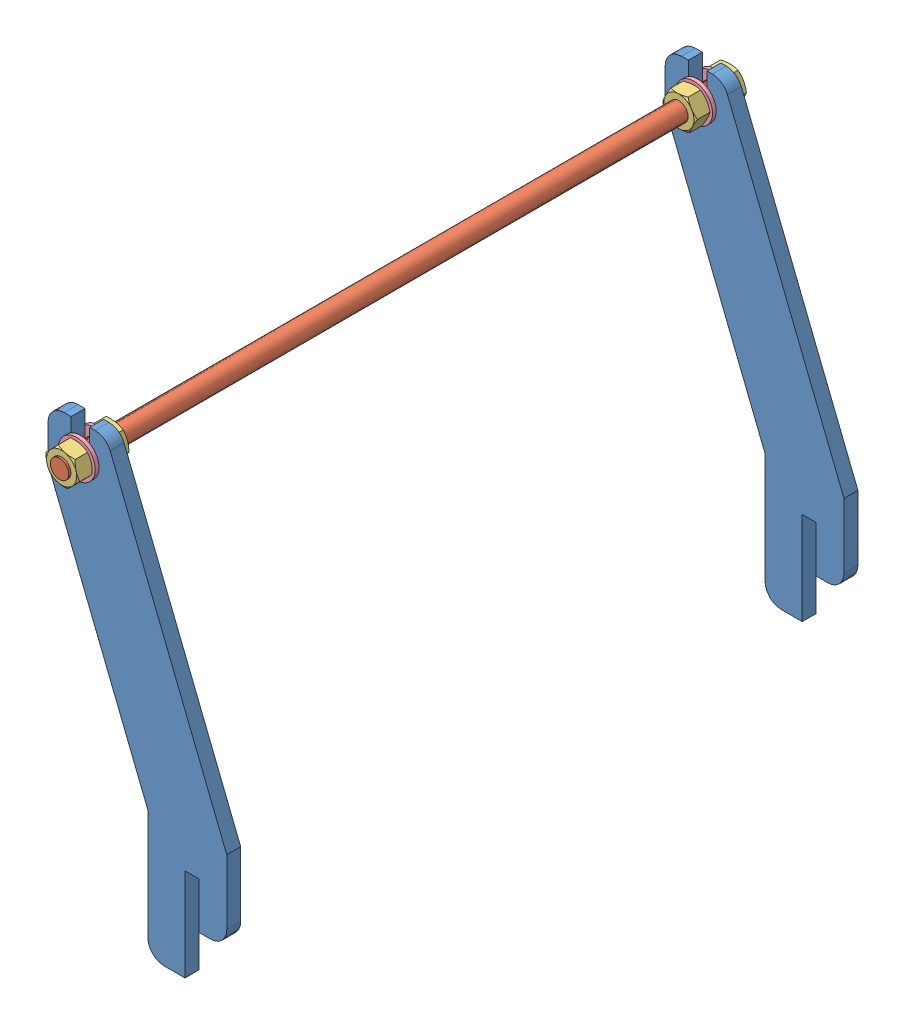
SolidWorks assembly Assembly spool-holder, configuration Valor predeterminado. Lengths in mm.
Overall size (77.07 185 290).
11 component instances, 4 part files, 22 mates.
Components (placement in the parent):
- spool-holder-1: spool-holder [Valor predeterminado] at (-111.4364 -194.1927 182) size (77.07 185 6)
- spool-holder-2: spool-holder [Valor predeterminado] at (-111.4364 -194.1927 448) size (77.07 185 6)
- Threaded Rod DIN 975 - M8 x 290-1: Threaded Rod DIN 975 - M8 x 290 [Valor predeterminado] at (42.0823 58.8982 318) size (8 8 290)
- Nut DIN 934 - M8-1: Nut DIN 934 - M8 [Valor predeterminado] at (42.0823 58.8982 177.15) x (0 0 -1) z (0.514233 0.857651 0) size (6.5 13 15.01)
- Washer DIN 125A - M8-1: Washer DIN 125A - M8 [Valor predeterminado] at (42.0823 58.8982 182) x (0 0 -1) z (0.898402 -0.439174 0) size (1.6 16 16)
- Washer DIN 125A - M8-2: Washer DIN 125A - M8 [Valor predeterminado] at (42.0823 58.8982 454) x (0 0 1) z (-0.984953 -0.17282 0) size (1.6 16 16)
- Nut DIN 934 - M8-2: Nut DIN 934 - M8 [Valor predeterminado] at (42.0823 58.8982 458.85) x (0 0 1) z (-0.69932 -0.714809 0) size (6.5 13 15.01)
- Washer DIN 125A - M8-3: Washer DIN 125A - M8 [Valor predeterminado] at (42.0823 58.8982 188) x (0 0 1) z (-0.848382 0.529384 0) size (1.6 16 16)
- Nut DIN 934 - M8-3: Nut DIN 934 - M8 [Valor predeterminado] at (42.0823 58.8982 192.85) x (0 0 1) z (-0.545075 0.838387 0) size (6.5 13 15.01)
- Nut DIN 934 - M8-4: Nut DIN 934 - M8 [Valor predeterminado] at (42.0823 58.8982 443.15) x (0 0 -1) z (-0.332092 0.943247 0) size (6.5 13 15.01)
- Washer DIN 125A - M8-4: Washer DIN 125A - M8 [Valor predeterminado] at (42.0823 58.8982 448) x (0 0 -1) z (0.981681 0.190531 0) size (1.6 16 16)
Mates (geometry in assembly coordinates):
- Concêntrico1: concentric: cylinder of assembly; cylinder of assembly; cylinder of spool-holder-1 through (42.0823 58.8982 188) axis (0 0 -1) radius 4; cylinder of spool-holder-2 through (42.0823 58.8982 454) axis (0 0 -1) radius 4
- Distância1: distance = 272 mm: plane of assembly; plane of assembly; plane of spool-holder-2 through (42.0823 58.8982 454) normal (0 0 1); plane of spool-holder-1 through (42.0823 58.8982 182) normal (0 0 -1)
- Coincidente1: coincident: plane of assembly; plane of assembly; plane of spool-holder-1 through (71.1512 -106.1018 188) normal (-1 0 0); plane of spool-holder-2 through (71.1512 -106.1018 454) normal (-1 0 0)
- Concêntrico2: concentric: cylinder of assembly; cylinder of assembly; cylinder of spool-holder-2 through (42.0823 58.8982 454) axis (0 0 -1) radius 4; cylinder of Threaded Rod DIN 975 - M8 x 290-1 through (42.0823 58.8982 463) axis (0 0 -1) radius 4
- Simétrico1: symmetric: plane of assembly; plane of assembly; plane of spool-holder-1 through (42.0823 58.8982 182) normal (0 0 -1); plane of spool-holder-2 through (42.0823 58.8982 454) normal (0 0 1); plane of assembly
- Coincidente2: coincident: plane of assembly through (0 0 318) normal (0 0 1); plane of Threaded Rod DIN 975 - M8 x 290-1 through (42.0823 58.8982 318) normal (0 0 1); plane of assembly
- Concêntrico3: concentric: cylinder of assembly; cylinder of assembly; cylinder of Nut DIN 934 - M8-1 through (42.0823 58.8982 173.9) axis (0 0 1) radius 3.4; cylinder of Washer DIN 125A - M8-1 through (42.0823 58.8982 180.4) axis (0 0 1) radius 4.2
- Coincidente3: coincident: plane of assembly; plane of assembly; plane of Nut DIN 934 - M8-1 through (38.2227 52.461 180.4) normal (0 0 1); plane of Washer DIN 125A - M8-1 through (42.0823 58.8982 180.4) normal (0 0 -1)
- Coincidente4: coincident: plane of assembly; plane of assembly; plane of Washer DIN 125A - M8-2 through (42.0823 58.8982 455.6) normal (0 0 1); plane of Nut DIN 934 - M8-2 through (47.3311 64.2632 455.6) normal (0 0 -1)
- Concêntrico4: concentric: cylinder of assembly; cylinder of assembly; cylinder of Washer DIN 125A - M8-2 through (42.0823 58.8982 455.6) axis (0 0 -1) radius 4.2; cylinder of Nut DIN 934 - M8-2 through (42.0823 58.8982 462.1) axis (0 0 -1) radius 3.4
- Coincidente5: coincident: plane of assembly; plane of assembly; plane of Washer DIN 125A - M8-3 through (42.0823 58.8982 189.6) normal (0 0 1); plane of Nut DIN 934 - M8-3 through (46.1734 52.6056 189.6) normal (0 0 -1)
- Concêntrico5: concentric: cylinder of assembly; cylinder of assembly; cylinder of Washer DIN 125A - M8-3 through (42.0823 58.8982 189.6) axis (0 0 -1) radius 4.2; cylinder of Nut DIN 934 - M8-3 through (42.0823 58.8982 196.1) axis (0 0 -1) radius 3.4
- Coincidente6: coincident: plane of assembly; plane of assembly; plane of Nut DIN 934 - M8-4 through (44.5749 51.8186 446.4) normal (0 0 1); plane of Washer DIN 125A - M8-4 through (42.0823 58.8982 446.4) normal (0 0 -1)
- Concêntrico6: concentric: cylinder of assembly; cylinder of assembly; cylinder of Nut DIN 934 - M8-4 through (42.0823 58.8982 439.9) axis (0 0 1) radius 3.4; cylinder of Washer DIN 125A - M8-4 through (42.0823 58.8982 446.4) axis (0 0 1) radius 4.2
- Concêntrico7: concentric: cylinder of assembly; cylinder of assembly; cylinder of Threaded Rod DIN 975 - M8 x 290-1 through (42.0823 58.8982 463) axis (0 0 -1) radius 4; cylinder of Washer DIN 125A - M8-1 through (42.0823 58.8982 180.4) axis (0 0 1) radius 4.2
- Concêntrico8: concentric: cylinder of assembly; cylinder of assembly; cylinder of Threaded Rod DIN 975 - M8 x 290-1 through (42.0823 58.8982 463) axis (0 0 -1) radius 4; cylinder of Washer DIN 125A - M8-3 through (42.0823 58.8982 189.6) axis (0 0 -1) radius 4.2
- Concêntrico9: concentric: cylinder of assembly; cylinder of assembly; cylinder of Threaded Rod DIN 975 - M8 x 290-1 through (42.0823 58.8982 463) axis (0 0 -1) radius 4; cylinder of Washer DIN 125A - M8-4 through (42.0823 58.8982 446.4) axis (0 0 1) radius 4.2
- Concêntrico10: concentric: cylinder of assembly; cylinder of assembly; cylinder of Threaded Rod DIN 975 - M8 x 290-1 through (42.0823 58.8982 463) axis (0 0 -1) radius 4; cylinder of Washer DIN 125A - M8-2 through (42.0823 58.8982 455.6) axis (0 0 -1) radius 4.2
- Coincidente7: coincident: plane of assembly; plane of assembly; plane of spool-holder-1 through (42.0823 58.8982 188) normal (0 0 1); plane of Washer DIN 125A - M8-3 through (42.0823 58.8982 188) normal (0 0 -1)
- Coincidente8: coincident: plane of assembly; plane of assembly; plane of spool-holder-1 through (42.0823 58.8982 182) normal (0 0 -1); plane of Washer DIN 125A - M8-1 through (42.0823 58.8982 182) normal (0 0 1)
- Coincidente9: coincident: plane of assembly; plane of assembly; plane of spool-holder-2 through (42.0823 58.8982 448) normal (0 0 -1); plane of Washer DIN 125A - M8-4 through (42.0823 58.8982 448) normal (0 0 1)
- Coincidente10: coincident: plane of assembly; plane of assembly; plane of spool-holder-2 through (42.0823 58.8982 454) normal (0 0 1); plane of Washer DIN 125A - M8-2 through (42.0823 58.8982 454) normal (0 0 -1)
